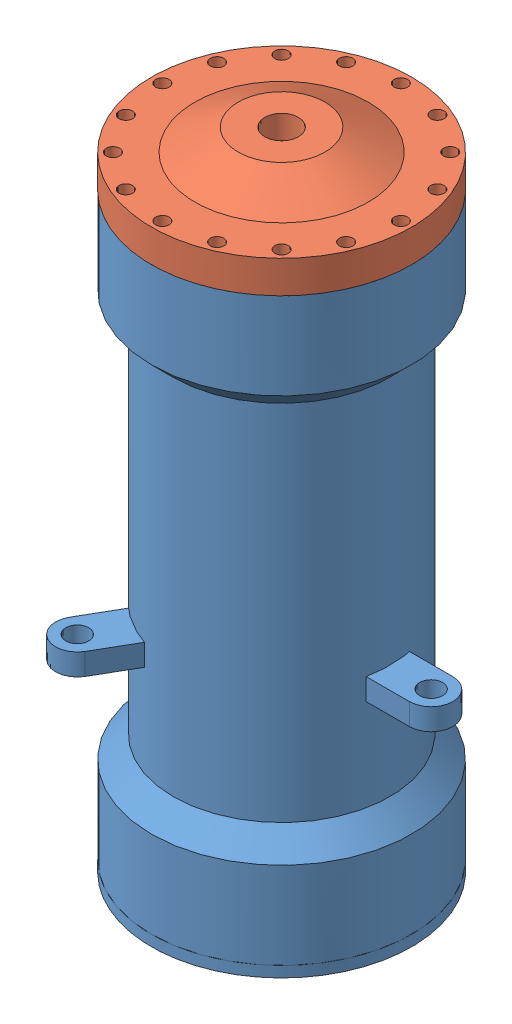
SolidWorks assembly cooling channel engine 3, configuration Default. Lengths in mm.
Overall size (176.52 377.8 177.16).
3 component instances, 3 part files, 7 mates.
Components (placement in the parent):
- slot cooling jacket 6-1: slot cooling jacket 6 [Default] at origin size (176.52 346.05 177.16)
- dome_2-1: dome_2 [Default] at (0 50.8 0) size (152.4 31.75 152.4)
- impinging injector_slot_film_cooling-1: impinging injector_slot_film_cooling [Default] at (0 -6.35 0) size (98.42 25.4 98.42)
Mates (geometry in assembly coordinates):
- Coincident1: coordinate: point of slot cooling jacket 6-1
- Concentric1: concentric aligned: cylinder of slot cooling jacket 6-1 through (0 19.05 69.85) axis (0 1 0) radius 3.4544; cylinder of dome_2-1 through (0 38.1 69.85) axis (0 1 0) radius 3.9688
- Concentric2: concentric aligned: cylinder of slot cooling jacket 6-1 through (0 -277.9245 0) axis (0 -1 0) radius 76.2; cylinder of dome_2-1 through (0 31.75 0) axis (0 -1 0) radius 76.2
- Coincident2: coincident anti-aligned: plane of slot cooling jacket 6-1 through (-76.2 19.05 0) normal (0 1 0); plane of dome_2-1 through (-76.2 19.05 0) normal (0 -1 0)
- Concentric3: concentric anti-aligned: cylinder of slot cooling jacket 6-1 through (0 0 0) axis (0 -1 0) radius 46.0375; cylinder of impinging injector_slot_film_cooling-1 through (0 12.7 0) axis (0 1 0) radius 43.2181
- Coincident3: coincident anti-aligned: plane of slot cooling jacket 6-1 through (-50.8 0 0) normal (0 1 0); plane of impinging injector_slot_film_cooling-1 through (-46.0375 0 0) normal (0 -1 0)
- Coincident4: coincident aligned: plane of slot cooling jacket 6-1 through (0 0 0) normal (0 0 1); plane of impinging injector_slot_film_cooling-1 through (0 -6.35 0) normal (0 0 1)
